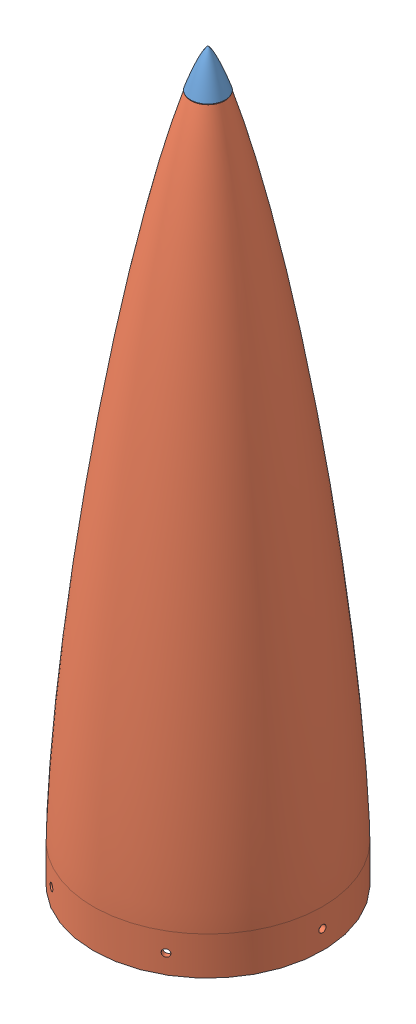
SolidWorks assembly 000077_R01_NOSE_CONE_ASSM, configuration Default. Lengths in mm.
Overall size (304.8 1128.44 304.8).
2 component instances, 2 part files, 1 mates.
Components (placement in the parent):
- 000076-R01_NOSE_CONE_TIP-2: 000076-R01_NOSE_CONE_TIP [Default] at (999.0121 907.2868 995.4719) x (0.00913 -0.999958 0.000472) z (-0.051617 0 0.998667) size (51.36 45.99 45.99)
- 000075-R01_NOSE_CONE-1: 000075-R01_NOSE_CONE [Default] at (999.0121 906.3634 995.4719) x (0 -1 0) z (0 0 1) size (1128.44 304.8 304.8)
Mates (geometry in assembly coordinates):
- Coincident1: coincident anti-aligned: axis of 000076-R01_NOSE_CONE_TIP-2 through (999.0121 890.7312 995.4719) axis (0 1 0); line of 000075-R01_NOSE_CONE-1 through (999.0121 968.0082 995.4719) axis (0 -1 0)
